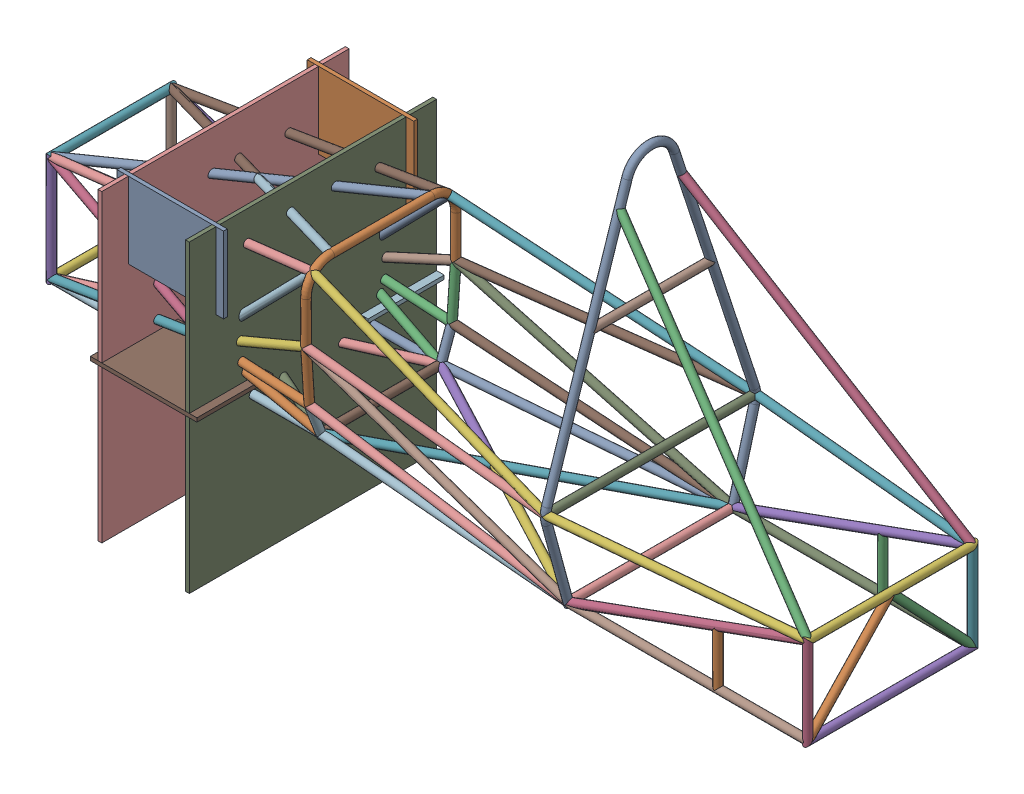
SolidWorks assembly Teal Team Jig Assembly, configuration Default. Lengths in mm.
Overall size (2625.4 1667.85 825.5).
7 component instances, 6 part files, 18 mates.
Components (placement in the parent):
- University_of_Portland_Chassis_006-1: University_of_Portland_Chassis_006 [Default<As Machined>] at origin size (2625.4 1211.08 727.61)
- Teal Jig 2-1: Teal Jig 2 [Default] at (666.75 38.1 0) x (0 0 -1) z (1 0 0) size (825.5 1016 12.7)
- Teal Jig 1-1: Teal Jig 1 [Default] at (374.65 38.1 0) x (0 0 -1) z (1 0 0) size (825.5 1016 12.7)
- teal jig 3-1: teal jig 3 [Default] at (520.7 44.45 285.75) size (355.6 12.7 254)
- teal jig 4-1: teal jig 4 [Default] at (520.7 44.45 -285.75) x (-1 0 0) z (0 0 -1) size (355.6 12.7 254)
- Teal Jig 5-1: Teal Jig 5 [Default] at (-951.304 570.2799 317.5) size (355.6 254 12.7)
- Teal Jig 5-2: Teal Jig 5 [Default] at (-951.304 570.2799 -317.5) size (355.6 254 12.7)
Mates (geometry in assembly coordinates):
- Distance1: distance = 685.8 mm anti-aligned: plane of Teal Jig 2-1 through (673.1 38.1 0) normal (1 0 0)
- Distance2: distance = 457.2 mm aligned: plane of Teal Jig 2-1 through (673.1 -469.9 412.75) normal (0 -1 0)
- Coincident4: coincident: point of Teal Jig 2-1
- Distance3: distance = 457.2 mm aligned: plane of Teal Jig 1-1 through (381 -469.9 412.75) normal (0 -1 0)
- Distance4: distance = 381 mm aligned: plane of Teal Jig 1-1 through (368.3 38.1 0) normal (-1 0 0)
- Coincident8: coincident: unknown of Teal Jig 1-1
- Distance5: distance = 50.8 mm aligned: plane of teal jig 3-1 through (520.7 38.1 285.75) normal (0 -1 0)
- Coincident10: coincident aligned: plane of Teal Jig 1-1 through (381 546.1 412.75) normal (0 0 1); plane of teal jig 3-1 through (342.9 50.8 412.75) normal (0 0 1)
- Distance6: distance = 25.4 mm aligned: plane of teal jig 3-1 through (342.9 50.8 158.75) normal (-1 0 0); plane of Teal Jig 1-1 through (368.3 38.1 0) normal (-1 0 0)
- Coincident16: coincident aligned: plane of Teal Jig 1-1 through (381 546.1 -412.75) normal (0 0 -1); plane of teal jig 4-1 through (698.5 50.8 -412.75) normal (0 0 -1)
- Distance8: distance = 25.4 mm aligned: plane of teal jig 4-1 through (342.9 50.8 -158.75) normal (-1 0 0); plane of Teal Jig 1-1 through (368.3 38.1 0) normal (-1 0 0)
- Coincident18: coincident aligned: plane of teal jig 3-1 through (520.7 50.8 285.75) normal (0 1 0); plane of teal jig 4-1 through (520.7 50.8 -285.75) normal (0 1 0)
- Coincident19: coincident aligned: plane of Teal Jig 1-1 through (381 546.1 412.75) normal (0 1 0); plane of Teal Jig 5-1 through (342.9 546.1 323.85) normal (0 1 0)
- Coincident21: coincident anti-aligned: plane of Teal Jig 1-1 through (381 546.1 311.15) normal (0 0 1); plane of Teal Jig 5-1 through (-951.304 570.2799 311.15) normal (0 0 -1)
- Coincident22: coincident anti-aligned: plane of Teal Jig 1-1 through (368.3 38.1 0) normal (-1 0 0); plane of Teal Jig 5-1 through (368.3 292.1 323.85) normal (1 0 0)
- Coincident23: coincident anti-aligned: plane of Teal Jig 1-1 through (381 546.1 -311.15) normal (0 0 -1); plane of Teal Jig 5-2 through (-951.304 570.2799 -311.15) normal (0 0 1)
- Coincident24: coincident anti-aligned: plane of Teal Jig 2-1 through (673.1 38.1 0) normal (1 0 0); plane of Teal Jig 5-2 through (673.1 419.1 -311.15) normal (-1 0 0)
- Coincident25: coincident aligned: plane of Teal Jig 2-1 through (673.1 546.1 412.75) normal (0 1 0); plane of Teal Jig 5-2 through (342.9 546.1 -311.15) normal (0 1 0)
